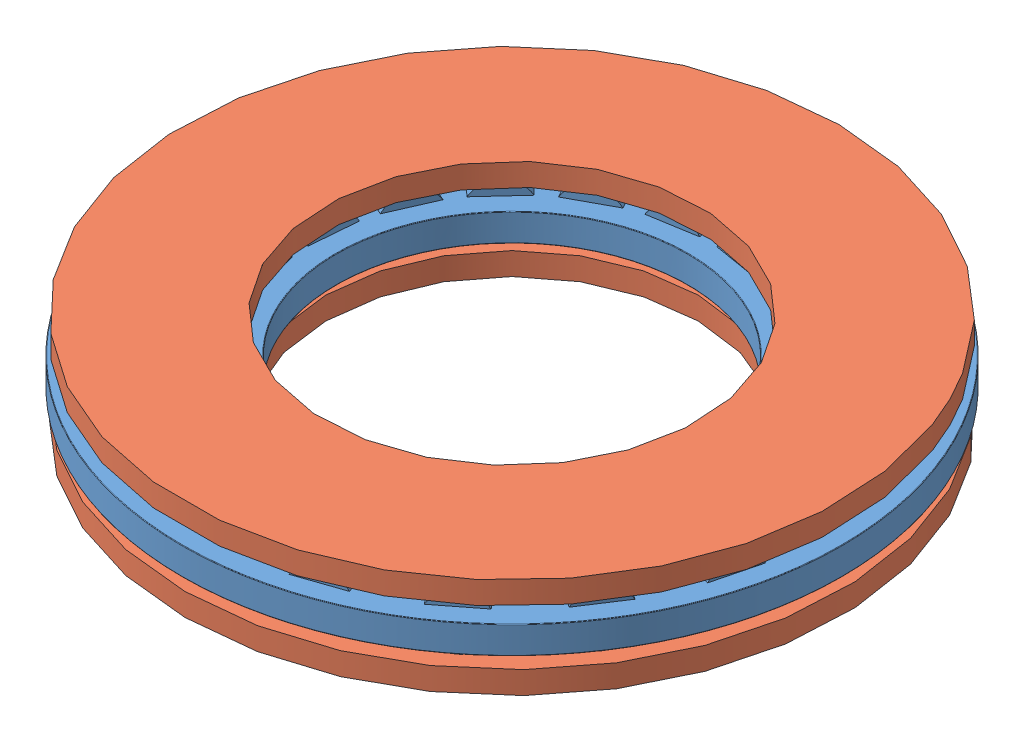
SolidWorks assembly .5 thrust needle bearing, configuration Default. Lengths in mm.
Overall size (31.61 3.61 31.61).
3 component instances, 2 part files, 4 mates.
Components (placement in the parent):
- 5909K310_THRUST NEEDLE-ROLLER BRNG-1: 5909K310_THRUST NEEDLE-ROLLER BRNG [5909K31] at (3.051 14.6085 19.8762) size (23.81 1.98 23.81)
- 5909K44_THRUST NEEDLE-ROLLER BRNG-1: 5909K44_THRUST NEEDLE-ROLLER BRNG [5909K45] at (3.051 13.6163 19.8762) x (0 -1 0) z (0 0 1) size (0.81 23.62 23.62)
- 5909K44_THRUST NEEDLE-ROLLER BRNG-2: 5909K44_THRUST NEEDLE-ROLLER BRNG [5909K45] at (3.051 16.4135 19.8762) x (0 -1 0) z (-0.897969 0 0.440058) size (0.81 23.62 23.62)
Mates (geometry in assembly coordinates):
- Concentric1: concentric anti-aligned: circle of 5909K310_THRUST NEEDLE-ROLLER BRNG-1; cylinder of 5909K44_THRUST NEEDLE-ROLLER BRNG-2 through (3.051 15.6007 19.8762) axis (0 1 0) radius 6.731
- Concentric2: concentric anti-aligned: cylinder of 5909K310_THRUST NEEDLE-ROLLER BRNG-1 through (3.051 13.6163 19.8762) axis (0 -1 0) radius 6.35; cylinder of 5909K44_THRUST NEEDLE-ROLLER BRNG-1 through (3.051 12.8035 19.8762) axis (0 1 0) radius 6.731
- Coincident1: coincident: point of 5909K310_THRUST NEEDLE-ROLLER BRNG-1; plane of 5909K44_THRUST NEEDLE-ROLLER BRNG-1 through (3.051 13.6163 19.8762) normal (0 1 0)
- Coincident2: coincident: point of 5909K310_THRUST NEEDLE-ROLLER BRNG-1; plane of 5909K44_THRUST NEEDLE-ROLLER BRNG-2 through (3.051 15.6007 19.8762) normal (0 -1 0)
